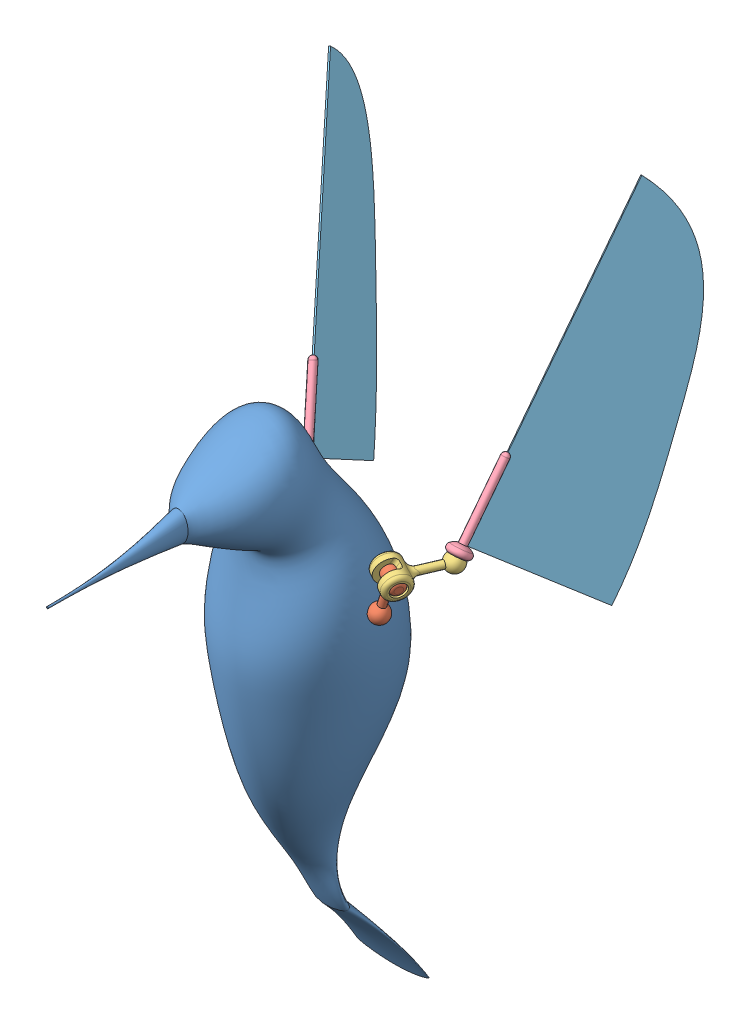
SolidWorks assembly overall, configuration 默认. Lengths in mm.
Overall size (58.13 93.16 81.23).
11 component instances, 5 part files, 8 mates.
Components (placement in the parent):
- torso-1: torso [默认] at (-20.7345 26.6787 48.7682) size (23.56 78.6 50.67)
- humerus-2: humerus [默认] at (-10.5307 0.2954 20.4983) x (0.26049 0.962245 -0.078932) z (0.891021 -0.208115 0.403448) size (7.2 2.4 4)
- ulna_radius-1: ulna_radius [默认] at (-6.5227 5.2356 14.1949) x (-0.416241 -0.019846 0.909038) z (0.891021 -0.208115 0.403448) size (9.45 3.5 4)
- humerus-3: humerus [默认] at (-30.9307 0.2954 20.4983) x (-0.092574 -0.045767 -0.994653) z (-0.971046 0.225094 0.08002) size (7.2 2.4 4)
- ulna_radius-2: ulna_radius [默认] at (-31.9463 -0.0156 9.0491) x (0.085031 0.01264 0.996298) z (0.971046 -0.225094 -0.08002) size (9.45 3.5 4)
- wingF-1: wingF [默认] at (-46.1704 5.2895 9.4463) x (-0.368203 0.817393 -0.443052) z (0.884338 0.160799 -0.43828) size (41.9 19.69 5.17)
  - manus-1: manus [默认] at (-9.3977 0.8371 11.9) size (12.32 3 4.04)
  - wing-1: wing [默认] at (-7.4977 0.8371 11.9) x (-1 0 0) z (0 0 -1) size (40 18.13 2.67)
- wingF-2: wingF [默认] at (-17.0403 9.2038 3.9841) x (-0.000666 0.790482 -0.612485) z (0.912141 0.251522 0.323627) size (41.9 19.69 5.17)
  - manus-1: manus [默认] at (-9.3977 0.8371 11.9) size (12.32 3 4.04)
  - wing-1: wing [默认] at (-7.4977 0.8371 11.9) x (-1 0 0) z (0 0 -1) size (40 18.13 2.67)
Mates (geometry in assembly coordinates):
- 同心2: concentric aligned: cylinder of humerus-2 through (-7.4462 4.6904 20.9105) axis (-0.891021 0.208115 -0.403448) radius 1; cylinder of ulna_radius-1 through (-7.4462 4.6904 20.9105) axis (-0.891021 0.208115 -0.403448) radius 1
- 同心3: concentric: sphere of torso-1; sphere of humerus-2
- 重合1: coincident aligned: plane of humerus-2 through (-7.4462 4.6904 20.9105) normal (0.891021 -0.208115 0.403448); plane of ulna_radius-1 through (-7.4462 4.6904 20.9105) normal (0.891021 -0.208115 0.403448)
- 同心5: concentric: sphere of torso-1; sphere of humerus-3
- 同心6: concentric anti-aligned: cylinder of humerus-3 through (-33.3357 0.5168 15.685) axis (0.971046 -0.225094 -0.08002) radius 1; cylinder of ulna_radius-2 through (-29.4515 -0.3836 15.365) axis (-0.971046 0.225094 0.08002) radius 1
- 重合2: coincident aligned: plane of humerus-3 through (-29.4515 -0.3836 15.365) normal (0.971046 -0.225094 -0.08002); plane of ulna_radius-2 through (-29.4515 -0.3836 15.365) normal (0.971046 -0.225094 -0.08002)
- 同心7: concentric: sphere of ulna_radius-2; sphere of wingF-1/manus-1
- 同心8: concentric: sphere of ulna_radius-1; sphere of wingF-2/manus-1
